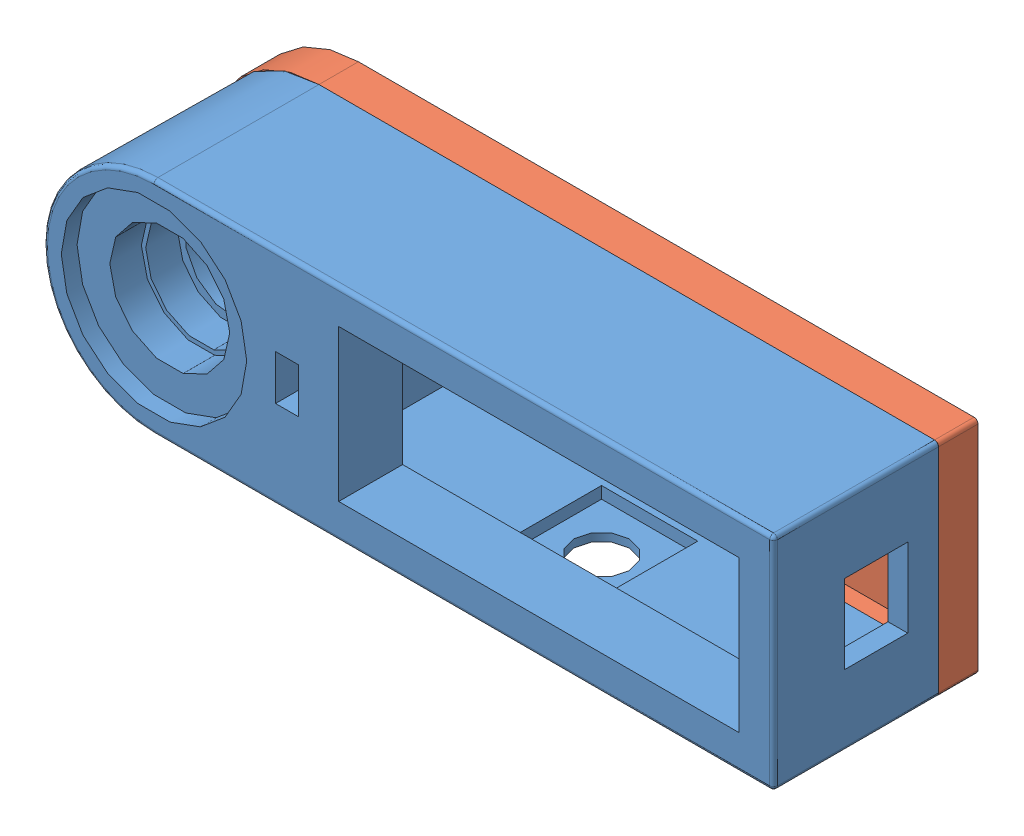
SolidWorks assembly Latency_IPCam, configuration По умолчанию. Lengths in mm.
Overall size (92.5 28 25.9).
2 component instances, 2 part files, 2 mates.
Components (placement in the parent):
- Latency_IPCam-1: Latency_IPCam [По умолчанию] at origin size (92.5 28 23)
- Крышка^Latency_IPCam-1: Крышка^Latency_IPCam [По умолчанию] at (-39.25 0 2.1) x (0 1 0) z (0 0 -1) size (28 92.5 5) (virtual)
Mates (geometry in assembly coordinates):
- Совпадение4: coincident anti-aligned: plane of Latency_IPCam-1 through (-39.25 0 2.1) normal (0 0 -1); plane of Крышка^Latency_IPCam-1 through (-39.25 0 2.1) normal (0 0 1)
- Концентричный1: concentric anti-aligned: cylinder of Latency_IPCam-1 through (-39.25 0 23) axis (0 0 -1) radius 14; cylinder of Крышка^Latency_IPCam-1 through (-39.25 0 -2.9) axis (0 0 1) radius 14
